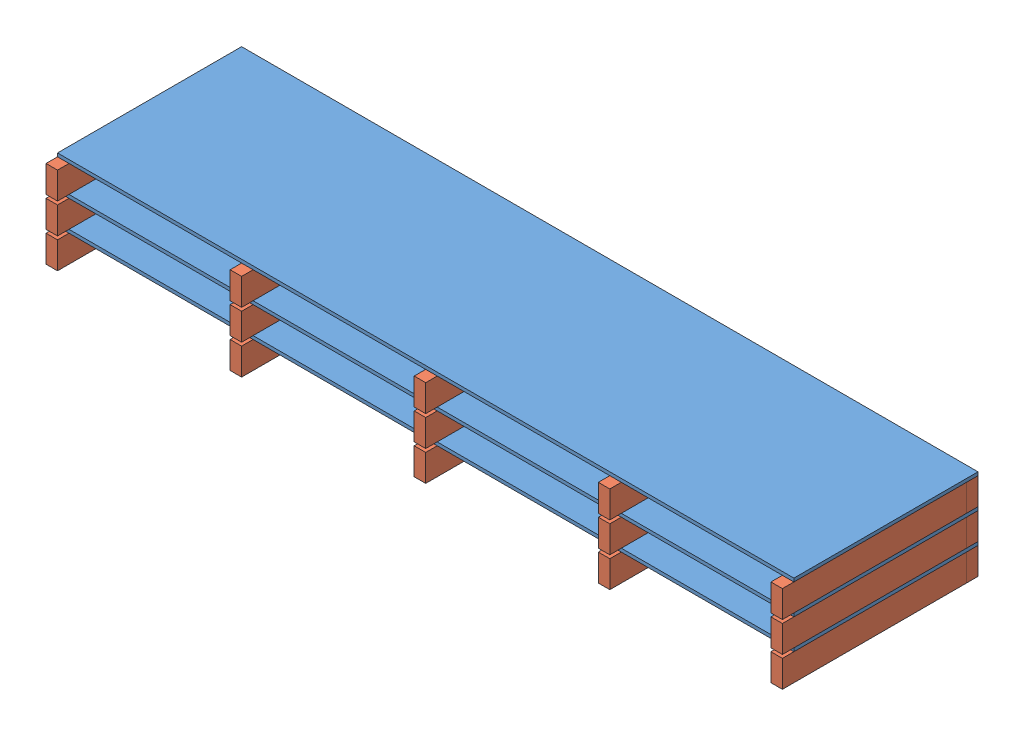
SolidWorks assembly Stock, configuration Default. Lengths in mm.
Overall size (2438.4 300.04 647.7).
24 component instances, 2 part files, 6 mates.
Components (placement in the parent):
- Shelf-1: Shelf [Default] at (-1191.0865 -104.201 699.3128) size (2438.4 100.01 647.7)
  - Plywood-1: Plywood [2ftX8ft] at (2465.4186 472.2515 -308.2621) x (0 0 1) z (0 -1 0) size (609.6 2438.4 11.11)
  - 2x4-6: 2x4 [8ft] at (27.0186 372.239 -308.2621) x (0 1 0) z (1 0 0) size (88.9 38.1 2438.4)
  - 2x4-7: 2x4 [2ft] at (65.1186 372.239 -270.1621) x (0 1 0) z (0 0 1) size (88.9 38.1 609.6)
  - 2x4-9: 2x4 [2ft] at (674.7186 372.239 -270.1621) x (0 1 0) z (0 0 1) size (88.9 38.1 609.6)
  - 2x4-10: 2x4 [2ft] at (1284.3186 372.239 -270.1621) x (0 1 0) z (0 0 1) size (88.9 38.1 609.6)
  - 2x4-11: 2x4 [2ft] at (1893.9186 372.239 -270.1621) x (0 1 0) z (0 0 1) size (88.9 38.1 609.6)
  - 2x4-12: 2x4 [2ft] at (2427.3186 461.139 -270.1621) x (0 -1 0) z (0 0 1) size (88.9 38.1 609.6)
- Shelf-2: Shelf [Default] at (-1191.0865 -204.2135 699.3128) size (2438.4 100.01 647.7)
  - Plywood-1: Plywood [2ftX8ft] at (2465.4186 472.2515 -308.2621) x (0 0 1) z (0 -1 0) size (609.6 2438.4 11.11)
  - 2x4-6: 2x4 [8ft] at (27.0186 372.239 -308.2621) x (0 1 0) z (1 0 0) size (88.9 38.1 2438.4)
  - 2x4-7: 2x4 [2ft] at (65.1186 372.239 -270.1621) x (0 1 0) z (0 0 1) size (88.9 38.1 609.6)
  - 2x4-9: 2x4 [2ft] at (674.7186 372.239 -270.1621) x (0 1 0) z (0 0 1) size (88.9 38.1 609.6)
  - 2x4-10: 2x4 [2ft] at (1284.3186 372.239 -270.1621) x (0 1 0) z (0 0 1) size (88.9 38.1 609.6)
  - 2x4-11: 2x4 [2ft] at (1893.9186 372.239 -270.1621) x (0 1 0) z (0 0 1) size (88.9 38.1 609.6)
  - 2x4-12: 2x4 [2ft] at (2427.3186 461.139 -270.1621) x (0 -1 0) z (0 0 1) size (88.9 38.1 609.6)
- Shelf-3: Shelf [Default] at (-1191.0865 -4.1885 699.3128) size (2438.4 100.01 647.7)
  - Plywood-1: Plywood [2ftX8ft] at (2465.4186 472.2515 -308.2621) x (0 0 1) z (0 -1 0) size (609.6 2438.4 11.11)
  - 2x4-6: 2x4 [8ft] at (27.0186 372.239 -308.2621) x (0 1 0) z (1 0 0) size (88.9 38.1 2438.4)
  - 2x4-7: 2x4 [2ft] at (65.1186 372.239 -270.1621) x (0 1 0) z (0 0 1) size (88.9 38.1 609.6)
  - 2x4-9: 2x4 [2ft] at (674.7186 372.239 -270.1621) x (0 1 0) z (0 0 1) size (88.9 38.1 609.6)
  - 2x4-10: 2x4 [2ft] at (1284.3186 372.239 -270.1621) x (0 1 0) z (0 0 1) size (88.9 38.1 609.6)
  - 2x4-11: 2x4 [2ft] at (1893.9186 372.239 -270.1621) x (0 1 0) z (0 0 1) size (88.9 38.1 609.6)
  - 2x4-12: 2x4 [2ft] at (2427.3186 461.139 -270.1621) x (0 -1 0) z (0 0 1) size (88.9 38.1 609.6)
Mates (geometry in assembly coordinates):
- Coincident1: coincident aligned: plane of Shelf-3/2x4-7 through (-1164.0679 368.0505 1038.7507) normal (-1 0 0); plane of Shelf-1/2x4-7 through (-1164.0679 268.038 1038.7507) normal (-1 0 0)
- Coincident2: coincident aligned: plane of Shelf-3/2x4-7 through (-1164.0679 368.0505 1038.7507) normal (-1 0 0); plane of Shelf-2/2x4-7 through (-1164.0679 168.0255 1038.7507) normal (-1 0 0)
- Coincident3: coincident aligned: plane of Shelf-3/2x4-7 through (-1125.9679 368.0505 1038.7507) normal (0 0 1); plane of Shelf-1/2x4-7 through (-1125.9679 268.038 1038.7507) normal (0 0 1)
- Coincident4: coincident aligned: plane of Shelf-3/2x4-7 through (-1125.9679 368.0505 1038.7507) normal (0 0 1); plane of Shelf-2/2x4-7 through (-1125.9679 168.0255 1038.7507) normal (0 0 1)
- Coincident5: coincident anti-aligned: plane of Shelf-1/Plywood-1 through (1274.3321 368.0505 391.0507) normal (0 1 0); plane of Shelf-3/2x4-6 through (1274.3321 368.0505 391.0507) normal (0 -1 0)
- Coincident6: coincident anti-aligned: plane of Shelf-1/2x4-6 through (1274.3321 268.038 391.0507) normal (0 -1 0); plane of Shelf-2/Plywood-1 through (1274.3321 268.038 391.0507) normal (0 1 0)
